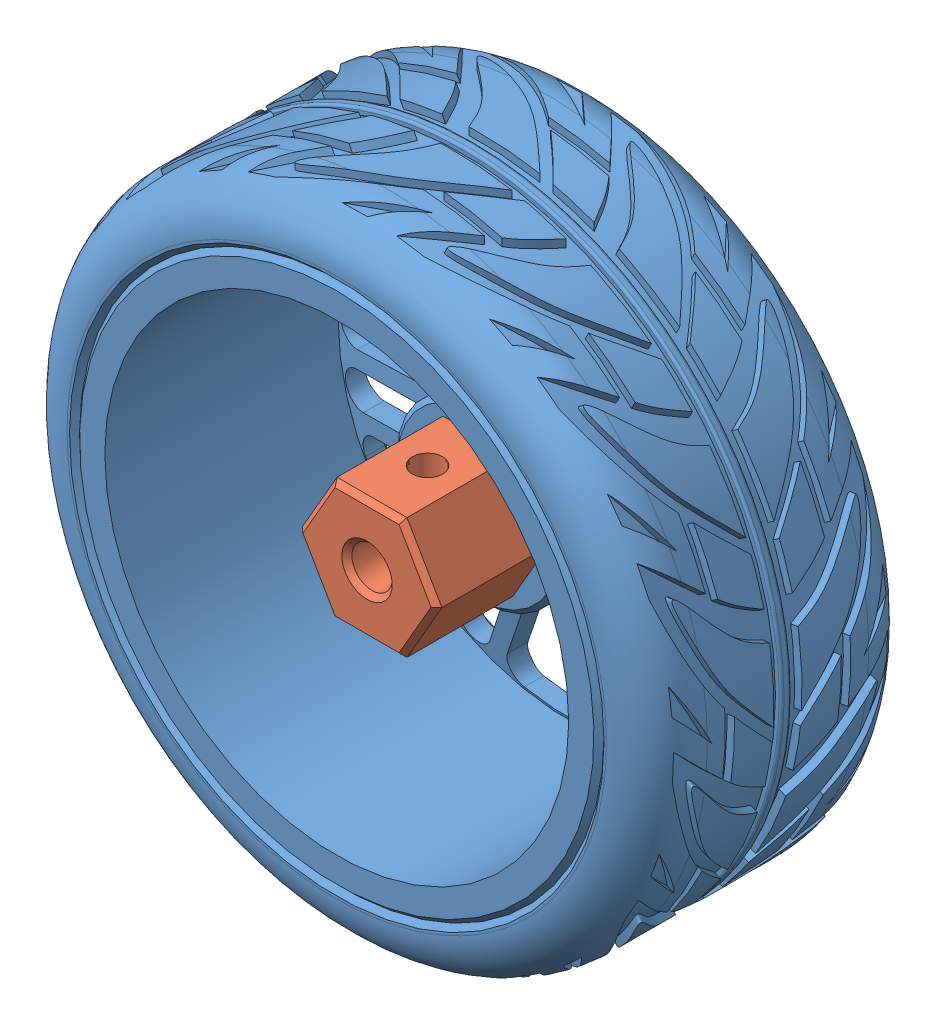
SolidWorks assembly Wheel_assembly, configuration Default. Lengths in mm.
Overall size (64.63 64.74 26).
3 component instances, 3 part files, 4 mates.
Components (placement in the parent):
- wheel-1: wheel [Default] at (22.0397 36.954 35.458) size (64.63 64.74 26)
- wheel_connector-1: wheel_connector [Default] at (22.0397 36.954 58.458) x (-0.5 -0.866025 0) z (0 0 -1) size (13.86 12 15)
- Wheet_nut-1: Wheet_nut [Default] at (22.0397 36.954 41.458) x (1 0 0) z (0 1 0) size (7 8.75 7)
Mates (geometry in assembly coordinates):
- Coincident1: coincident anti-aligned: plane of wheel-1 through (22.0397 24.954 43.458) normal (0 0 1); plane of wheel_connector-1 through (25.5038 30.954 43.458) normal (0 0 -1)
- Coincident2: coincident anti-aligned: plane of wheel-1 through (15.1115 36.954 43.458) normal (0.866025 0.5 0); plane of wheel_connector-1 through (18.5756 30.954 43.458) normal (-0.866025 -0.5 0)
- Coincident3: coincident anti-aligned: plane of wheel-1 through (18.5756 42.954 43.458) normal (0.866025 -0.5 0); plane of wheel_connector-1 through (15.1115 36.954 43.458) normal (-0.866025 0.5 0)
- Concentric1: concentric anti-aligned: cylinder of wheel-1 through (22.0397 36.954 39.458) axis (0 0 1) radius 2; cylinder of Wheet_nut-1 through (22.0397 36.954 47.458) axis (0 0 -1) radius 2
